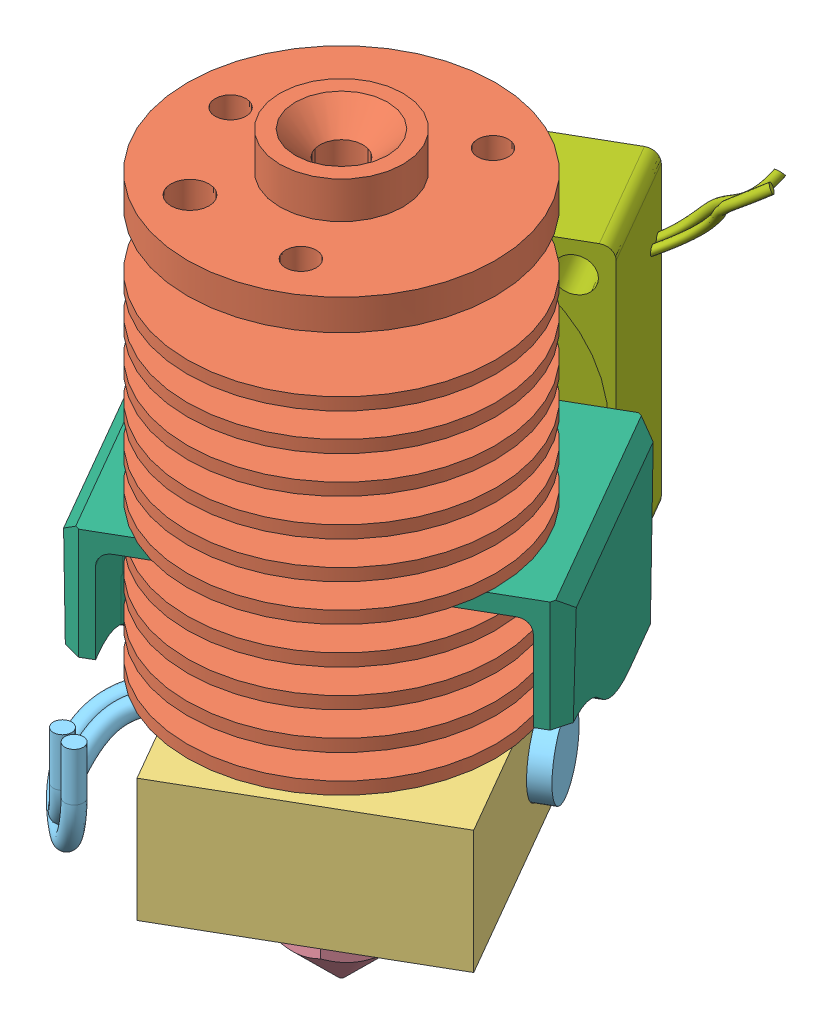
SolidWorks assembly Hot end, configuration Default. Lengths in mm.
Overall size (38.99 59.5 50.43).
7 component instances, 7 part files, 18 mates.
Components (placement in the parent):
- Heat break-1: Heat break [Default] at (-2.0709 -13.6407 -0.1704) size (6 16 6)
- Heat sink-1: Heat sink [Default] at (-2.0709 -5.6407 -0.1704) x (-1 0 0) z (0 0 -1) size (25 38 25)
- Hot block-1: Hot block [Default] at (-2.8209 -8.6407 -1.4694) x (-0.866025 0 0.5) z (0 -1 0) size (20 19 10)
- Nozzle 0.4-1: Nozzle 0.4 [Default] at (-2.0709 -26.1407 -0.1704) x (0.5 0 -0.866025) z (0.866025 0 0.5) size (10.17 12.5 8)
- Resistance-1: Resistance [Predeterminado] at (3.2144 -13.1407 -11.0161) x (-0.5 0 -0.866025) z (-0.866025 0 0.5) size (21.94 11.59 29.05)
- E3D Cooler Fan Support_v5-1: E3D Cooler Fan Support_v5 [Predeterminado] at (-7.0709 20.7593 -8.8307) x (-0.5 0 -0.866025) z (-0.866025 0 0.5) size (19.5 14 30.45)
- fan25-1: fan25 [Predeterminado] at (-8.8209 5.5093 -11.8618) x (-0.866025 0 0.5) z (-0.5 0 -0.866025) size (34.02 28.5 10.1)
Mates (geometry in assembly coordinates):
- Concentric1: concentric aligned: cylinder of Heat break-1 through (-2.0709 -0.6407 -0.1704) axis (0 -1 0) radius 3; cylinder of Heat sink-1 through (-2.0709 -5.6407 -0.1704) axis (0 -1 0) radius 2.5
- Coincident4: coincident anti-aligned: plane of Heat break-1 through (-2.0709 -13.6407 -0.1704) normal (0 -1 0); plane of Nozzle 0.4-1 through (-2.0709 -13.6407 -0.1704) normal (0 1 0)
- Paralelo1: parallel anti-aligned: plane of Heat sink-1 through (-2.0709 -5.6407 -0.1704) normal (0 0 -1); plane of assembly through (0 0 0) normal (0 0 1)
- Ángulo1: planar angle = 3.665191 rad aligned: plane of Hot block-1 through (1.0894 -18.6407 -14.6967) normal (-0.5 0 -0.866025); plane of assembly through (0 0 0) normal (0 0 1)
- Paralelo2: parallel aligned: plane of Hot block-1 through (10.5894 -18.6407 1.7578) normal (0.866025 0 -0.5); plane of Nozzle 0.4-1 through (2.5479 -18.6407 -0.1704) normal (0.866025 0 -0.5)
- Coincidente3: coincident anti-aligned: plane of Heat break-1 through (-2.0709 2.3593 -0.1704) normal (0 1 0); plane of Heat sink-1 through (0.4291 2.3593 -0.1704) normal (0 -1 0)
- Concéntrica132: concentric anti-aligned: cylinder of Heat break-1 through (-2.0709 -7.6407 -0.1704) axis (0 -1 0) radius 3; cylinder of Hot block-1 through (-2.0709 -18.6407 -0.1704) axis (0 1 0) radius 2.5
- Concéntrica133: concentric aligned: cylinder of Heat break-1 through (-2.0709 -7.6407 -0.1704) axis (0 -1 0) radius 3; cylinder of Nozzle 0.4-1 through (-2.0709 -13.6407 -0.1704) axis (0 -1 0) radius 3
- Coincidente196: coincident anti-aligned: plane of Hot block-1 through (-2.8209 -18.6407 -1.4694) normal (0 -1 0); plane of Nozzle 0.4-1 through (-2.0709 -18.6407 -0.1704) normal (0 1 0)
- Concéntrica134: concentric anti-aligned: cylinder of Hot block-1 through (3.2144 -13.1407 -11.0161) axis (-0.866025 0 0.5) radius 3.05; cylinder of Resistance-1 through (-12.3741 -13.1407 -2.0161) axis (0.866025 0 -0.5) radius 3
- Distancia7: distance = 1.5 mm aligned: plane of Hot block-1 through (10.5894 -18.6407 1.7578) normal (0.866025 0 -0.5); plane of Resistance-1 through (4.5134 -13.1407 -11.7661) normal (0.866025 0 -0.5)
- Paralelo3: parallel aligned: plane of Hot block-1 through (-2.8209 -18.6407 -1.4694) normal (0 -1 0); plane of Resistance-1
- Concéntrica135: concentric anti-aligned: cylinder of Heat sink-1 through (-2.0709 9.3593 -0.1704) axis (0 1 0) radius 3.5; cylinder of E3D Cooler Fan Support_v5-1 through (-2.0709 30.19 -0.1704) axis (0 -1 0) radius 3.5
- Coincidente197: coincident anti-aligned: plane of Heat sink-1 through (-2.0709 5.3593 3.3296) normal (0 1 0); plane of E3D Cooler Fan Support_v5-1 through (-2.0709 5.3593 -0.1704) normal (0 -1 0)
- Paralelo4: parallel aligned: plane of E3D Cooler Fan Support_v5-1 through (4.1695 -7.2407 -19.3618) normal (-0.5 0 -0.866025); plane of Hot block-1 through (1.0894 -18.6407 -14.6967) normal (-0.5 0 -0.866025)
- Coincidente199: coincident anti-aligned: plane of E3D Cooler Fan Support_v5-1 through (4.1695 -7.2407 -19.3618) normal (-0.5 0 -0.866025); plane of fan25-1 through (-8.8209 5.5093 -11.8618) normal (0.5 0 0.866025)
- Concéntrica136: concentric anti-aligned: cylinder of E3D Cooler Fan Support_v5-1 through (-11.6976 -4.7407 3.6556) axis (-0.5 0 -0.866025) radius 1.45; cylinder of fan25-1 through (-22.6976 -4.7407 -15.397) axis (0.5 0 0.866025) radius 1.4
- Concéntrica137: concentric anti-aligned: cylinder of E3D Cooler Fan Support_v5-1 through (6.0559 -4.7407 -6.5944) axis (-0.5 0 -0.866025) radius 1.45; cylinder of fan25-1 through (-4.9441 -4.7407 -25.647) axis (0.5 0 0.866025) radius 1.4
